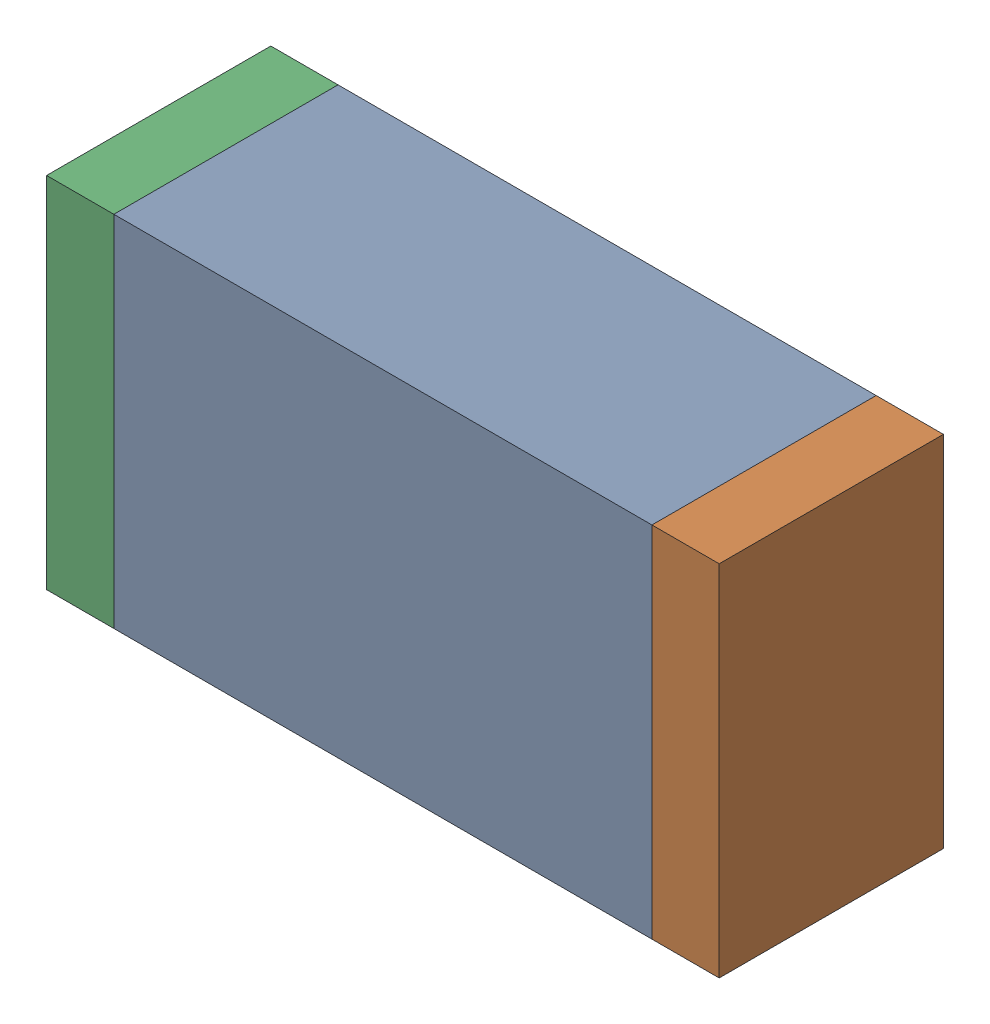
SolidWorks assembly R12, configuration Default. Lengths in mm.
Overall size (1.5 0.8 0.5).
6 component instances, 2 part files, 0 mates.
Components (placement in the parent):
- 836752368-1: 836752368 [Default] at (128.9 38.5 0) size (1.2 0.8 0.5)
  - Extruded-1: Extruded [Default] at origin size (1.2 0.8 0.5)
- 836752496-1: 836752496 [Default] at (129.575 38.5 0) size (0.15 0.8 0.5)
  - Extruded_2-1: Extruded_2 [Default] at origin size (0.15 0.8 0.5)
- 836752496-2: 836752496 [Default] at (128.225 38.5 0) size (0.15 0.8 0.5)
  - Extruded_2-1: Extruded_2 [Default] at origin size (0.15 0.8 0.5)
